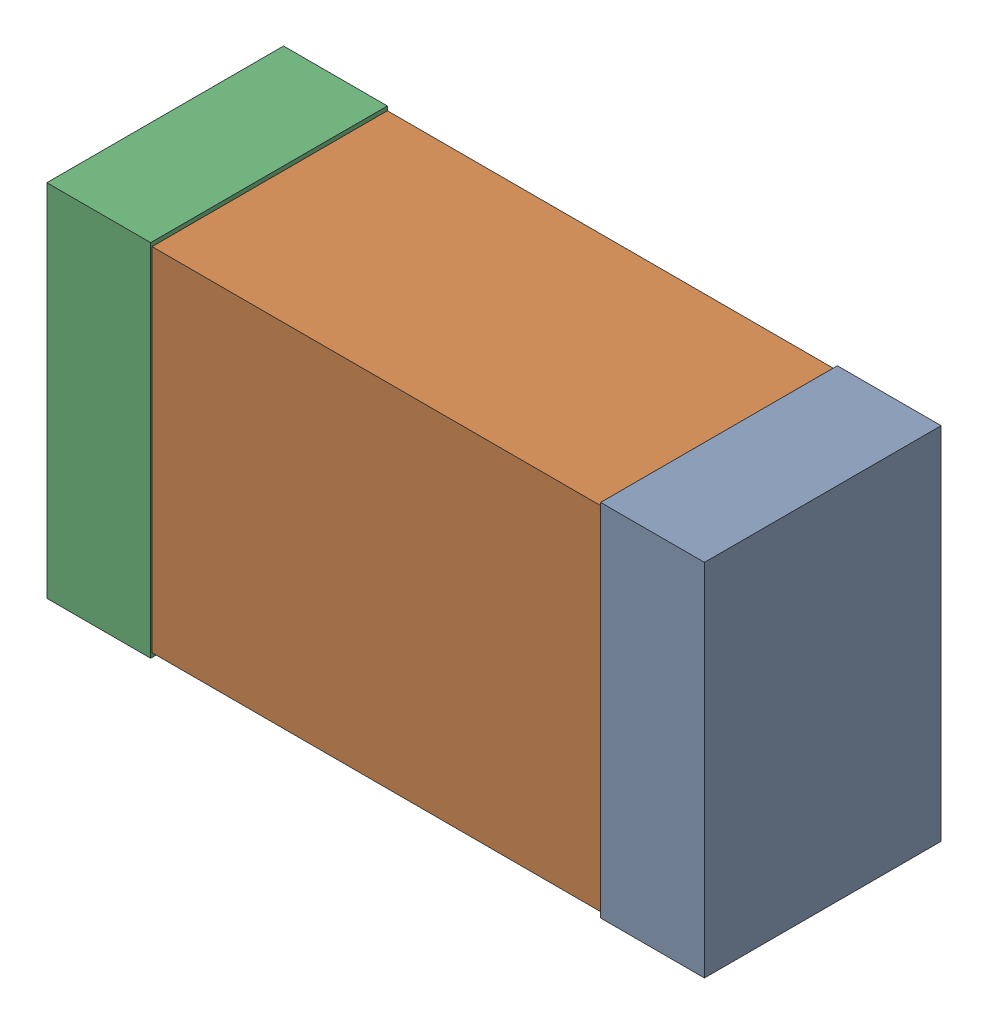
SolidWorks assembly R4Kanaloa_v2.0.0_Motor, configuration Default. Lengths in mm.
Overall size (2.38 1.3 0.85).
6 component instances, 2 part files, 0 mates.
Components (placement in the parent):
- 352877648-1: 352877648 [Default] at (74.347 118.9502 0) size (0.38 1.3 0.85)
  - Extruded_14-1: Extruded_14 [Default] at origin size (0.38 1.3 0.85)
- 352877904-1: 352877904 [Default] at (73.347 118.9502 0) size (2.2 1.27 0.85)
  - Extruded_18-1: Extruded_18 [Default] at origin size (2.2 1.27 0.85)
- 352877648-2: 352877648 [Default] at (72.347 118.9502 0) size (0.38 1.3 0.85)
  - Extruded_14-1: Extruded_14 [Default] at origin size (0.38 1.3 0.85)
